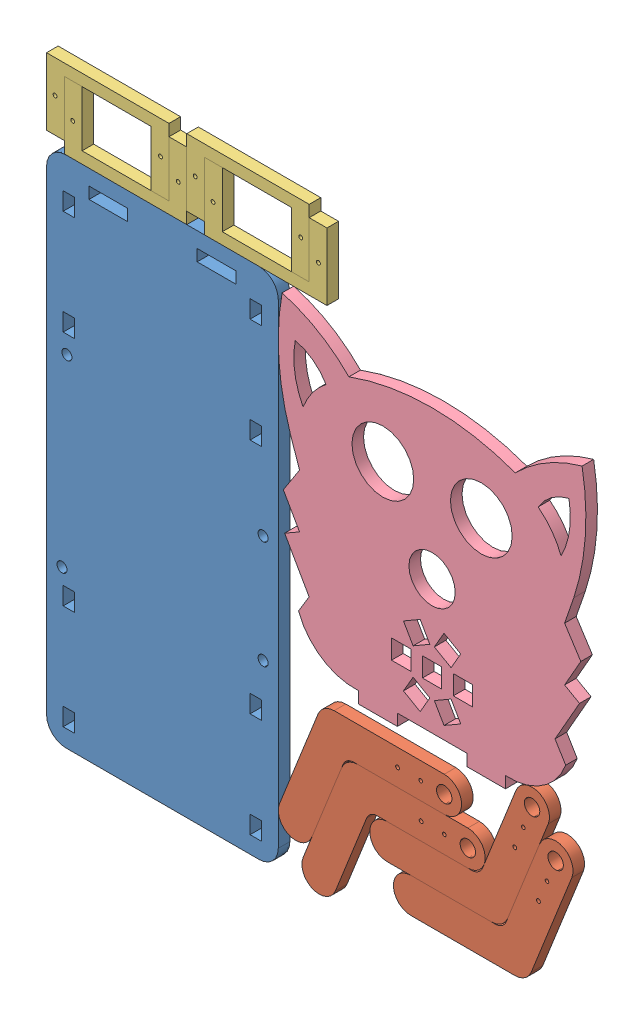
SolidWorks assembly mia_laser_cutting, configuration Default. Lengths in mm.
Overall size (150 170.12 3).
10 component instances, 4 part files, 32 mates.
Components (placement in the parent):
- Base-1: Base [Default] at (2.0044 -169.2894 -3) x (1 0 0) z (0 -1 0) size (60 3 133)
- leg-1: leg [Default] at (79.2182 -163.3326 0) x (0.369302 0.929309 0) z (-0.929309 0.369302 0) size (46.53 3 35.49)
- leg-2: leg [Default] at (117.2177 -177.3298 -3) x (1 0 0) z (0 -1 0) size (46.53 3 35.49)
- leg-3: leg [Default] at (85.3263 -172.3326 0) x (0.369302 0.929309 0) z (-0.929309 0.369302 0) size (46.53 3 35.49)
- leg-4: leg [Default] at (111.1097 -168.3298 -3) x (1 0 0) z (0 -1 0) size (46.53 3 35.49)
- servo_support-5: servo_support [Default] at (38.3044 -43.8894 -3) x (-1 0 0) z (0 0 1) size (31.7 17.4 3)
- servo_support-6: servo_support [Default] at (2.0044 -58.2894 -3) size (31.7 17.4 3)
- servo_support-7: servo_support [Default] at (38.3044 -58.2894 -3) size (31.7 17.4 3)
- servo_support-8: servo_support [Default] at (42.9044 -43.8894 0) x (1 0 0) z (0 0 -1) size (31.7 17.4 3)
- cat_face_v1-1: cat_face_v1 [Default] at (60.6456 -65.5255 -3) x (0 -1 0) z (0 0 1) size (82.31 79.65 3)
Mates (geometry in assembly coordinates):
- Coincident4: coincident: plane of leg-2 through (133.8248 278.924 570.4243) normal (0 0 1); plane of leg-4 through (127.7168 287.924 570.4243) normal (0 0 1)
- Coincident10: coincident: plane of leg-2 through (118.2097 256.9387 570.4243) normal (0 1 0); plane of leg-4 through (90.1917 256.9387 570.4243) normal (0 -1 0)
- Coincident11: coincident: plane of leg-2 through (129.6429 280.5859 570.4243) normal (-0.929309 0.369302 0); plane of leg-4 through (131.8987 286.2621 570.4243) normal (0.929309 -0.369302 0)
- Coincident14: coincident: plane of leg-1 through (104.9755 274.9387 567.4243) normal (0 -1 0); plane of leg-3 through (111.0836 274.9387 567.4243) normal (0 1 0)
- Coincident15: coincident: plane of leg-1 through (78.7776 273.0466 567.4243) normal (0.929309 -0.369302 0); plane of leg-3 through (68.4305 247.0092 567.4243) normal (-0.929309 0.369302 0)
- Coincident16: coincident: plane of leg-2 through (133.8248 278.924 567.4243) normal (0 0 -1); plane of leg-3 through (111.0836 270.4387 567.4243) normal (0 0 -1)
- Coincident17: coincident: plane of leg-1 through (104.9755 279.4387 570.4243) normal (0 0 1); plane of leg-3 through (111.0836 270.4387 570.4243) normal (0 0 1)
- Coincident18: coincident: plane of leg-3 through (111.0836 265.9387 567.4243) normal (0 -1 0); plane of leg-4 through (112.1016 265.9387 570.4243) normal (0 1 0)
- Tangent1: tangent: cylinder of leg-3 through (111.0836 270.4387 567.4243) axis (0 0 1) radius 4.5; plane of leg-4 through (123.5349 289.5859 570.4243) normal (-0.929309 0.369302 0)
- Parallel1: parallel: plane of Base-1 through (7.0044 240.8473 0) normal (0 -1 0); plane of leg-2 through (96.2997 247.9387 570.4243) normal (0 -1 0)
- Tangent2: tangent: plane of Base-1 through (7.0044 240.8473 0) normal (0 -1 0); cylinder of leg-3 through (72.6124 245.3473 567.4243) axis (0 0 1) radius 4.5
- Tangent3: tangent: plane of Base-1 through (62.0044 245.8473 0) normal (1 0 0); cylinder of leg-1 through (66.5044 254.3473 567.4243) axis (0 0 1) radius 4.5
- Distance5: distance = 1 mm: plane of Base-1 through (2.0044 -189.2894 0) normal (-1 0 0); line of assembly
- Distance6: distance = 1 mm: plane of Base-1 through (7.0044 -194.2894 0) normal (0 -1 0); line of assembly
- Coincident35: coincident: plane of Base-1 through (57.0044 245.8473 0) normal (0 0 1); plane of servo_support-5 through (38.3044 391.2473 0) normal (0 0 1)
- Coincident37: coincident: plane of servo_support-5 through (38.3044 391.2473 0) normal (0 0 1); plane of servo_support-6 through (2.0044 376.8473 0) normal (0 0 1)
- Coincident38: coincident: plane of servo_support-5 through (33.7044 391.2473 0) normal (-1 0 0); plane of servo_support-6 through (33.7044 376.8473 0) normal (1 0 0)
- Coincident39: coincident: plane of servo_support-5 through (33.7044 376.8473 0) normal (0 1 0); plane of servo_support-6 through (29.1044 376.8473 0) normal (0 -1 0)
- Coincident40: coincident: plane of Base-1 through (7.0044 373.8473 0) normal (0 1 0); plane of servo_support-5 through (6.6044 373.8473 0) normal (0 -1 0)
- Coincident41: coincident: plane of Base-1 through (2.0044 245.8473 0) normal (-1 0 0); plane of servo_support-6 through (2.0044 394.2473 0) normal (-1 0 0)
- Coincident42: coincident: plane of servo_support-5 through (38.3044 373.8473 0) normal (1 0 0); plane of servo_support-7 through (38.3044 394.2473 0) normal (-1 0 0)
- Coincident43: coincident: plane of Base-1 through (57.0044 245.8473 0) normal (0 0 1); plane of servo_support-7 through (38.3044 376.8473 0) normal (0 0 1)
- Coincident44: coincident: plane of servo_support-6 through (33.7044 394.2473 0) normal (0 1 0); plane of servo_support-7 through (70.0044 394.2473 0) normal (0 1 0)
- Coincident45: coincident: plane of Base-1 through (57.0044 245.8473 0) normal (0 0 1); plane of servo_support-8 through (42.9044 391.2473 0) normal (0 0 1)
- Coincident47: coincident: plane of Base-1 through (7.0044 373.8473 0) normal (0 1 0); plane of servo_support-8 through (74.6044 373.8473 -3) normal (0 -1 0)
- Coincident48: coincident: plane of servo_support-7 through (42.9044 376.8473 0) normal (1 0 0); plane of servo_support-8 through (42.9044 373.8473 -3) normal (-1 0 0)
- Coincident49: coincident: plane of Base-1 through (57.0044 245.8473 0) normal (0 0 1); plane of cat_face_v1-1 through (79.179 359.8313 0) normal (0 0 1)
- Parallel3: parallel: plane of Base-1 through (7.0044 240.8473 0) normal (0 -1 0); plane of cat_face_v1-1 through (82.8269 288.5792 0) normal (0 -1 0)
- Tangent7: tangent: plane of Base-1 through (62.0044 245.8473 0) normal (1 0 0); cylinder of cat_face_v1-1 through (124.4748 359.8313 0) axis (0 0 -1) radius 62.4704
- Tangent8: tangent: cylinder of leg-4 through (127.7168 287.924 570.4243) axis (0 0 -1) radius 4.5; cylinder of cat_face_v1-1 through (121.8486 307.0846 0) axis (0 0 -1) radius 15.5391
- Width1: width: plane of ? through (57.0044 245.8473 0) normal (0 0 1)
- Coincident51: coincident: plane of Base-1 through (57.0044 -189.2894 0) normal (0 0 1); plane of leg-1 through (104.9755 -155.6981 0) normal (0 0 1)
